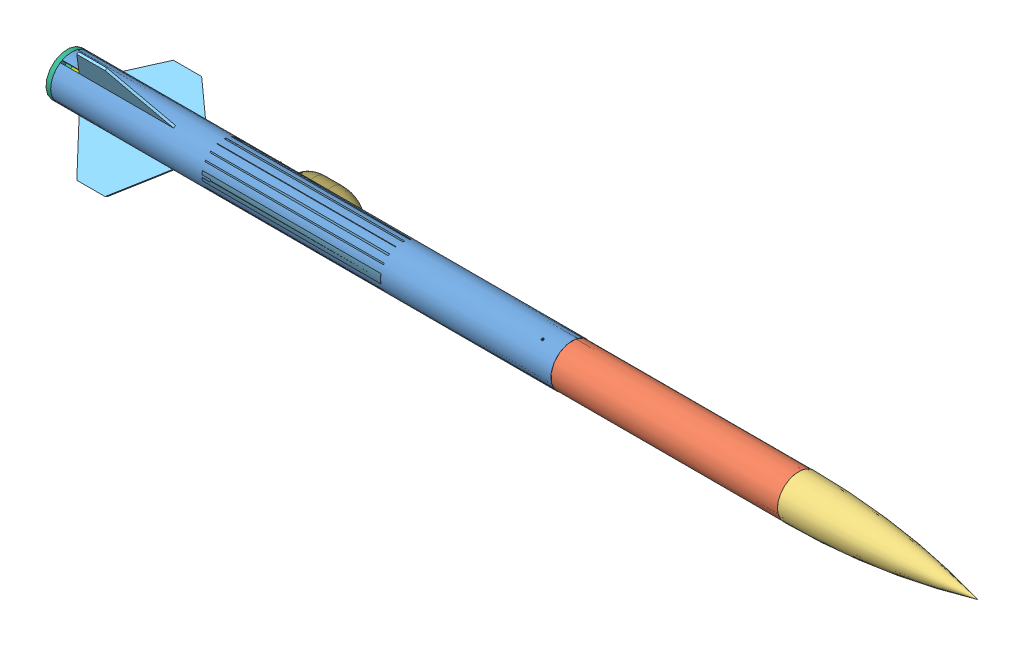
SolidWorks assembly Mudd III Medium Assembly, configuration Default. Lengths in mm.
Overall size (1225.55 149.96 129.87).
100 component instances, 55 part files, 34 mates.
Components (placement in the parent):
- Medium Booster Tube-1: Medium Booster Tube [Default] at (-372.2289 13.0481 9.9626) size (673.1 57.15 57.15)
- Medium Parachute Tube-1: Medium Parachute Tube [Default] at (300.8711 13.0481 9.9626) x (1 0 0) z (0 -0.816689 -0.577078) size (304.8 57.15 57.15)
- Medium Nose Cone-1: Medium Nose Cone [Default] at (542.1711 13.0481 9.9626) x (0 -0.965528 0.260297) z (0 0.260297 0.965528) size (57.15 304.8 57.15)
- Medium Coupler Tube-1: Medium Coupler Tube [Default] at (351.6711 13.0481 9.9626) x (-1 0 0) z (0 -0.866025 -0.5) size (101.6 53.98 53.98)
- Medium Fin-1: Medium Fin [Default] at (-346.8289 -10.8518 25.5943) x (1 0 0) z (0 -0.5 -0.866025) size (127 65.09 3.17)
- Medium Fin-2: Medium Fin [Default] at (-346.8289 38.5356 22.8447) x (1 0 0) z (0 -0.5 0.866025) size (127 65.09 3.17)
- Medium Fin-3: Medium Fin [Default] at (-346.8289 11.4606 -18.5513) x (1 0 0) z (0 1 0) size (127 65.09 3.17)
- Medium Motor Adapter-1: Medium Motor Adapter [Default] at (-372.2289 13.0481 9.9626) x (1 0 0) z (0 0.828794 0.559554) size (234.95 57.15 57.15)
- Medium Center Ring-1: Medium Center Ring [Default] at (-346.8289 13.0481 9.9626) x (0 0.296163 0.955137) z (-1 0 0) size (53.98 53.98 12.7)
- Medium Center Ring-2: Medium Center Ring [Default] at (-169.0289 13.0481 9.9626) x (0 0.277869 0.960619) z (-1 0 0) size (53.98 53.98 12.7)
- total assem-1: total assem [Default] at (-58.9172 86.7196 7.1089) x (0 1 0) z (-1 0 0) size (57.15 75.5 240.21)
  - small ccd assem-1: small ccd assem [Default] at (0.6838 4.0163 -14.4433) size (21.97 25.91 29.31)
    - CCD back card-1: CCD back card [Default] at (-63.2621 8.497 25.622) size (21.97 25.91 6.6)
    - CCD-1: CCD [Default] at (-74.2476 21.8241 33.115) x (0 0 1) z (0 -1 0) size (24.1 21.97 25.91)
  - transmitter-1: transmitter [Default] at (-74.5115 28.118 1.5267) x (1 0 0) z (0 0 -1) size (21.79 25.75 7.11)
  - holder piece full-1: holder piece full [Default] at (-73.6715 -24.6441 89.7205) x (0 0 1) z (-1 0 0) size (78.74 36.53 25.4)
  - shroud-1: shroud [Default] at (-73.6888 25.7213 35.9945) x (0.000325 0 -1) z (1 0 0.000325) size (87.63 29.9 39.12)
  - mirror piece 1by1inch-1: mirror piece 1by1inch [Default] at (-60.9715 15.1368 37.7322) x (1 0 0) z (0 -0.906308 0.422618) size (25.4 25.4 3.2)
  - Mudd III medium tube demo-1: Mudd III medium tube demo [Default] at (-73.666 -2.8537 250.8571) x (0 0 -1) z (0 1 0) size (240.21 57.15 57.15)
  - tab-1: tab [Default] at (-73.666 25.7213 -6.4951) x (0 0 -1) z (1 0 0) size (19.69 10.34 6.35)
- NewAvionicsBay2-1: NewAvionicsBay2 [Default] at (108.4854 -12.4721 24.3916) x (1 0 0) z (0 1 0) size (359.89 53.34 55.74)
  - AvionicsMainBoard-1: AvionicsMainBoard [Default] at (-136.1657 8.079 23.6534) size (349.25 53.34 3.81)
  - 9V battery-1: 9V battery [Default] at (-17.1552 23.2413 23.6534) x (1 0 0) z (0 0 -1) size (46.99 25.4 16.52)
  - IMUBoard-1: IMUBoard [Default] at (-199.5485 3.632 31.1574) x (1 0 0) z (0 0 -1) size (73 23 14.43)
    - IMUMainBoard-1: IMUMainBoard [Default] at (-36.8639 8.2406 13.8541) size (73 23 2)
    - MPXA4115-1: MPXA4115 [Default] at (18.9073 2.9523 15.8541) x (0 -1 0) z (0 0 1) size (18.12 12.32 7.62)
    - AD8608-1: AD8608 [Default] at (15.2114 -11.4075 13.8541) x (1 0 0) z (0 0 -1) size (5 6.4 1.2)
    - AD8608-2: AD8608 [Default] at (14.8718 -1.2991 13.8541) x (1 0 0) z (0 0 -1) size (5 6.4 1.2)
    - ADXL78-1: ADXL78 [Default] at (-6.9369 -1.9207 15.8541) x (0 -1 0) z (0 0 1) size (5 5 1.98)
    - REF19x-1: REF19x [Default] at (-22.4189 6.9447 15.8541) x (0 -1 0) z (0 0 1) size (5 6.2 1.75)
    - IDG300-1: IDG300 [Default] at (-3.0205 -1.1058 15.8541) size (6 6 1.4)
    - 53048-1410-1: 53048-1410 [Default] at (33.2198 -3.0194 17.6041) x (0 -1 0) z (1 0 0) size (19.25 5.8 5.5)
    - 53048-0310-1: 53048-0310 [Default] at (-34.0557 4.9779 17.6041) x (0 1 0) z (-1 0 0) size (5.5 5.8 5.5)
    - 53048-0410-1: 53048-0410 [Default] at (-34.0379 -2.2079 17.6041) x (0 1 0) z (-1 0 0) size (6.75 5.8 5.5)
    - 53048-0510-1: 53048-0510 [Default] at (-34.0353 -10.4916 17.6041) x (0 1 0) z (-1 0 0) size (8 5.8 5.5)
    - AccelDB-1: AccelDB [Default] at (-23.5295 2.2949 14.7757) x (0 1 0) z (1 0 0) size (17 11.63 4.63)
      - 3216Pkg-1: 3216Pkg [Default] at (-3.7758 3.176 4.084) x (0 1 0) z (0 0 1) size (3.2 1.6 1.6)
      - 1206Pkg-1: 1206Pkg [Default] at (-11.4283 4.1288 4.084) x (0 1 0) z (0 0 1) size (3.2 1.6 1.6)
      - 0805Pkg-1: 0805Pkg [Default] at (-10.2284 4.3883 7.259) x (0 1 0) z (0 0 1) size (2 1.25 1.25)
      - 0805Pkg-2: 0805Pkg [Default] at (-12.0972 4.3652 7.259) x (0 1 0) z (0 0 1) size (2 1.25 1.25)
      - ADXL320-1: ADXL320 [Default] at (-5.3524 7.1765 7.259) size (4 4 1.45)
      - AccelDB-1: AccelDB [Default] at (-15.2264 1.0784 5.684) size (17 8 1.57)
      - HeaderPin-2: HeaderPin [Default] at (0.7701 -0.5264 5.684) x (1 0 0) z (0 1 0) size (0.64 0.64 9.53)
      - HeaderPin-3: HeaderPin [Default] at (-14.903 -0.6387 5.684) x (1 0 0) z (0 1 0) size (0.64 0.64 9.53)
      - HeaderPin-4: HeaderPin [Default] at (-14.8947 -0.6469 7.894) x (1 0 0) z (0 1 0) size (0.64 0.64 9.53)
      - HeaderPin-5: HeaderPin [Default] at (0.7664 -0.543 7.894) x (1 0 0) z (0 1 0) size (0.64 0.64 9.53)
    - GyroDB-1: GyroDB [Default] at (-0.6385 5.9144 16.4856) x (1 0 0) z (0 -1 0) size (17 14.43 4.58)
      - GyroDBoard-1: GyroDBoard [Default] at (-12.0524 9.3685 -0.0049) size (17 10.7 1.57)
      - 3216Pkg-1: 3216Pkg [Default] at (-0.8029 4.0431 -1.6049) x (0 1 0) z (0 0 1) size (3.2 1.6 1.6)
      - 1206Pkg-1: 1206Pkg [Default] at (-4.4709 0.5573 -1.6049) x (0 1 0) z (0 0 1) size (3.2 1.6 1.6)
      - 1206Pkg-2: 1206Pkg [Default] at (-4.6902 4.9535 -1.6049) x (0 1 0) z (0 0 1) size (3.2 1.6 1.6)
      - 0805Pkg-1: 0805Pkg [Default] at (-7.0362 1.6074 1.4951) x (0 1 0) z (0 0 1) size (2 1.25 1.25)
      - 0805Pkg-2: 0805Pkg [Default] at (-7.0321 4.6376 1.5701) x (0 1 0) z (0 0 1) size (2 1.25 1.25)
      - IDG300-1: IDG300 [Default] at (-4.083 6.8921 1.5701) size (6 6 1.4)
      - HeaderPin-1: HeaderPin [Default] at (3.9124 3.0877 -0.6399) x (0.999938 -0.011165 0) z (-0.011165 -0.999938 0) size (0.64 0.64 9.53)
      - HeaderPin-2: HeaderPin [Default] at (3.8089 3.0739 1.5701) x (0.999992 0.00401 0) z (0.00401 -0.999992 0) size (0.64 0.64 9.53)
      - HeaderPin-3: HeaderPin [Default] at (-11.5657 2.5564 1.5701) x (1 0 0) z (0 -1 0) size (0.64 0.64 9.53)
      - HeaderPin-4: HeaderPin [Default] at (-11.5519 2.6099 -0.6399) x (1 0 0) z (0 -1 0) size (0.64 0.64 9.53)
    - AD8608-5: AD8608 [Default] at (-8.3767 -4.6541 13.8541) x (-1 0 0) z (0 0 -1) size (5 6.4 1.2)
    - AD8608-6: AD8608 [Default] at (-0.2194 4.1606 13.8541) x (-1 0 0) z (0 0 -1) size (5 6.4 1.2)
    - REF19x-3: REF19x [Default] at (-27.9582 6.764 13.8541) x (0 -1 0) z (0 0 -1) size (5 6.2 1.75)
  - SigCond-1: SigCond [Default] at (55.7433 7.466 27.9177) x (-1 0 0) z (0 0 -1) size (40 23 6.27)
    - SigCond-1: SigCond [Default] at (-14.6509 -4.244 10.6143) size (40 23 1.57)
    - AD8608-1: AD8608 [Default] at (3.1067 8.1664 10.6143) x (0 -1 0) z (0 0 -1) size (5 6.4 1.2)
    - AD8608-2: AD8608 [Default] at (8.6587 7.5077 12.1891) x (0 -1 0) z (0 0 1) size (5 6.4 1.2)
    - REF19x-1: REF19x [Default] at (2.8146 17.9328 12.1891) x (0 -1 0) z (0 0 1) size (5 6.2 1.75)
    - 53048-1010-1: 53048-1010 [Default] at (-11.8656 3.4034 13.9391) x (0 1 0) z (-1 0 0) size (14.25 5.8 5.5)
    - 53048-1210-1: 53048-1210 [Default] at (22.5911 4.1581 13.9391) x (0 -1 0) z (1 0 0) size (16.75 5.8 5.5)
  - SwitchPlate-1: SwitchPlate [Default] at (85.8509 10.5974 25.1267) x (0 1 0) z (0 0 1) size (31.75 24.13 13.32)
    - SwitchPlate-1: SwitchPlate [Default] at (-12.5007 -3.0767 8.6867) size (31.75 24.13 1.57)
    - ScrewSwitch-1: ScrewSwitch [Default] at (3.373 8.9378 10.2615) x (0 1 0) z (0 0 1) size (7.92 7.37 13.32)
  - 5VBoard-1: 5VBoard [Default] at (-89.5319 8.7054 29.3839) x (-1 0 0) z (0 0 -1) size (92.07 27.94 17.78)
    - 5VPower-1: 5VPower [Default] at (-41.4694 20.784 7.7625) size (92.08 27.94 1.57)
    - 9VClip-1: 9VClip [Default] at (14.6682 14.1315 9.3373) x (0 -1 0) z (-1 0 0) size (9.65 17.02 7.26)
    - 9VClip-2: 9VClip [Default] at (14.1531 0.4986 9.3373) x (0 -1 0) z (-1 0 0) size (9.65 17.02 7.26)
    - ScrewSwitch-1: ScrewSwitch [Default] at (28.3109 6.7817 9.3373) size (7.92 7.37 13.32)
  - RDASTransmitter-1: RDASTransmitter [Default] at (-146.7869 -1.9294 33.8134) size (95.9 28 17.4)
  - AntennaRDAS-1: AntennaRDAS [Default] at (-151.5106 12.0706 43.9644) x (0 0.94972 0.3131) z (0 -0.3131 0.94972) size (17.21 92.63 16.7)
  - 9V battery-2: 9V battery [Default] at (-85.0106 24.0842 20.0466) x (1 0 0) z (0 0 -1) size (46.99 25.4 16.52)
  - rdas started-1: rdas started [Default] at (22.7124 41.4238 33.8134) x (1 0 0) z (0 0 -1) size (94.13 28 20.9)
  - AvionicsForwardDisk-1: AvionicsForwardDisk [Default] at (93.3256 14.429 25.5203) x (0 0 -1) z (1 0 0) size (53.34 53.34 6.35)
  - AvionicsAftDisk-3: AvionicsAftDisk [Default] at (-243.2244 14.429 25.5584) x (0 0 1) z (-1 0 0) size (53.34 53.34 6.35)
  - patchbay-1: patchbay [Default] at (94.5977 -15.4317 39.9493) x (0 -1 0) z (1 0 0) size (35.05 35.05 16.14)
    - patchbay disk-1: patchbay disk [Default] at (-29.8607 14.429 5.0779) size (35.05 35.05 1.75)
    - 53048-0510-1: 53048-0510 [Default] at (-39.1051 14.4036 9.5805) x (0 -1 0) z (0 0 1) size (8 5.8 5.5)
    - 53048-1410-1: 53048-1410 [Default] at (-30.0832 5.1164 2.3279) x (-1 0 0) z (0 0 -1) size (19.25 5.8 5.5)
    - 53048-1010-1: 53048-1010 [Default] at (-31.8902 22.3247 2.3279) x (-1 0 0) z (0 0 -1) size (14.25 5.8 5.5)
    - patchbay pins-1: patchbay pins [Default] at (-14.7709 42.7152 6.8305) x (0 1 0) z (0 0 1) size (20 14 8.89)
- Ejection Assembly-1: Ejection Assembly [Default] at (258.3491 5.0129 22.6223) x (0 -0.14468 0.989478) z (-1 0 0) size (50.8 49.29 12.7)
  - Drogue Bulk Head (without aluminum)-1: Drogue Bulk Head (without aluminum) [Default] at (-13.689 6.119 0.658) size (50.8 49.29 3.81)
  - Drouge Bulk Head (with aluminum)-1: Drouge Bulk Head (with aluminum) [Default] at (-13.689 6.119 8.278) size (50.8 43.36 3.81)
  - Drogue Bulk Head Screw Insert-1: Drogue Bulk Head Screw Insert [Default] at (-13.689 12.215 13.358) x (1 0 0) z (0 1 0) size (19.05 12.7 19.05)
  - Booster Bulkhead Aluminum (with thread)-1: Booster Bulkhead Aluminum (with thread) [Default] at (-31.2912 -12.677 4.468) size (35.56 15.24 4.06)
  - Booster Bulkhead Aluminum (without thread)-1: Booster Bulkhead Aluminum (without thread) [Default] at (-31.2912 -12.677 8.532) size (35.56 15.24 4.06)
- Retention Assembly-1: Retention Assembly [Default] at (551.1746 -1.4552 15.5793) x (0 -0.709837 0.704366) z (-1 0 0) size (51.82 51.82 16)
  - Bulkhead3-1: Bulkhead3 [Default] at (-14.2512 6.2286 1.3835) size (50.8 50.8 3.81)
  - Booster Bulkhead-1: Booster Bulkhead [Default] at (-14.2512 6.2286 5.1935) size (51.82 51.82 3.81)
  - Booster Bulkhead Aluminum (without thread)-1: Booster Bulkhead Aluminum (without thread) [Default] at (3.5288 -1.3914 17.1315) x (-1 0 0) z (0 0 -1) size (35.56 15.24 4.06)
  - Booster Bulkhead Aluminum (with thread)-1: Booster Bulkhead Aluminum (with thread) [Default] at (-32.0312 -1.3914 1.1295) size (35.56 15.24 4.06)
  - Booster Bulkhead Aluminum (without thread)-2: Booster Bulkhead Aluminum (without thread) [Default] at (-32.0312 -1.3914 9.0035) size (35.56 15.24 4.06)
Mates (geometry in assembly coordinates):
- Concentric1: concentric aligned: cylinder of Medium Booster Tube-1; cylinder of Medium Parachute Tube-1
- Concentric2: concentric anti-aligned: cylinder of Medium Parachute Tube-1; cylinder of Medium Nose Cone-1
- Coincident2: coincident anti-aligned: plane of Medium Parachute Tube-1 through (605.6711 13.0481 9.9626) normal (1 0 0); plane of Medium Nose Cone-1 through (605.6711 39.1053 2.9378) normal (-1 0 0)
- Concentric3: concentric anti-aligned: cylinder of Medium Parachute Tube-1; cylinder of Medium Coupler Tube-1
- Distance1: distance = 50.8 mm aligned: plane of Medium Parachute Tube-1 through (300.8711 13.0481 9.9626) normal (-1 0 0); plane of Medium Coupler Tube-1 through (250.0711 13.0481 9.9626) normal (-1 0 0)
- Concentric4: concentric aligned: cylinder of Medium Booster Tube-1; cylinder of Medium Coupler Tube-1
- Concentric5: concentric aligned: cylinder of Medium Booster Tube-1; cylinder of Medium Motor Adapter-1
- Concentric8: concentric anti-aligned: cylinder of Medium Motor Adapter-1; cylinder of Medium Center Ring-1
- Concentric9: concentric anti-aligned: cylinder of Medium Motor Adapter-1; cylinder of Medium Center Ring-2
- Distance6: distance = 12.7 mm anti-aligned: plane of Medium Motor Adapter-1 through (-372.2289 13.0481 9.9626) normal (1 0 0); plane of Medium Center Ring-1 through (-359.5289 13.0481 9.9626) normal (-1 0 0)
- Distance8: distance = 25.4 mm aligned: plane of Medium Motor Adapter-1 through (-143.6289 13.0481 9.9626) normal (1 0 0); plane of Medium Center Ring-2 through (-169.0289 13.0481 9.9626) normal (1 0 0)
- Coincident36: coincident: line of Medium Fin-3; cylinder of Medium Motor Adapter-1
- Coincident37: coincident: line of Medium Fin-2; cylinder of Medium Motor Adapter-1
- Coincident38: coincident: line of Medium Fin-1; cylinder of Medium Motor Adapter-1
- Coincident39: coincident: line of Medium Fin-3; cylinder of Medium Motor Adapter-1
- Coincident40: coincident: line of Medium Fin-1; cylinder of Medium Motor Adapter-1
- Coincident42: coincident: line of Medium Fin-2; cylinder of Medium Motor Adapter-1
- Coincident43: coincident anti-aligned: plane of Medium Fin-2 through (-346.8289 36.9481 25.5943) normal (-1 0 0); plane of Medium Center Ring-1 through (-346.8289 13.0481 9.9626) normal (1 0 0)
- Coincident44: coincident anti-aligned: plane of Medium Fin-1 through (-346.8289 -12.4393 22.8447) normal (-1 0 0); plane of Medium Center Ring-1 through (-346.8289 13.0481 9.9626) normal (1 0 0)
- Coincident45: coincident anti-aligned: plane of Medium Fin-3 through (-346.8289 14.6356 -18.5513) normal (-1 0 0); plane of Medium Center Ring-1 through (-346.8289 13.0481 9.9626) normal (1 0 0)
- Parallel2: parallel anti-aligned: plane of Medium Booster Tube-1 through (-219.8289 11.4606 -18.6124) normal (0 1 0); plane of Medium Fin-3 through (-346.8289 11.4606 -75.7013) normal (0 -1 0)
- Parallel3: parallel anti-aligned: plane of Medium Booster Tube-1 through (-219.8289 47.6465 28.1049) normal (0 -0.5 0.866025); plane of Medium Fin-2 through (-346.8289 88.029 51.4197) normal (0 0.5 -0.866025)
- Coincident49: coincident anti-aligned: plane of Medium Booster Tube-1 through (-372.2289 13.0481 9.9626) normal (-1 0 0); plane of Medium Motor Adapter-1 through (-372.2289 13.0481 9.9626) normal (1 0 0)
- Concentric10: concentric anti-aligned: circle of Medium Coupler Tube-1 centre (250.0711 13.0481 9.9626) axis (-1 0 0); circle of NewAvionicsBay2-1/AvionicsForwardDisk-1 centre (208.1611 13.0481 9.9626) axis (1 0 0)
- Parallel5: parallel aligned: line of total assem-1/holder piece full-1; line of NewAvionicsBay2-1/AvionicsMainBoard-1
- Parallel6: parallel aligned: line of total assem-1/holder piece full-1; line of NewAvionicsBay2-1/AvionicsMainBoard-1
- Coincident58: coincident anti-aligned: plane of total assem-1/holder piece full-1 through (-52.8239 16.2231 5.2201) normal (1 0 0); plane of NewAvionicsBay2-1/AvionicsMainBoard-1 through (-52.8239 14.9912 5.2201) normal (-1 0 0)
- Parallel8: parallel aligned: plane of Medium Fin-3 through (-346.8289 14.6356 -75.7013) normal (0 1 0); plane of NewAvionicsBay2-1/AvionicsMainBoard-1 through (201.8111 14.9912 -16.7074) normal (0 1 0)
- Distance9: distance = 2.54 mm anti-aligned: plane of Medium Motor Adapter-1 through (-143.6289 13.0481 9.9626) normal (1 0 0); plane of NewAvionicsBay2-1/AvionicsAftDisk-3 through (-141.0889 13.0862 9.9626) normal (-1 0 0)
- Concentric11: concentric anti-aligned: circle of NewAvionicsBay2-1/AvionicsForwardDisk-1 centre (208.1611 13.0481 9.9626) axis (1 0 0); circle of Medium Coupler Tube-1 centre (250.0711 13.0481 9.9626) axis (-1 0 0)
- Concentric12: concentric aligned: circle of Medium Coupler Tube-1 centre (250.0711 13.0481 9.9626) axis (-1 0 0); circle of Ejection Assembly-1/Drogue Bulk Head (without aluminum)-1 centre (257.6911 13.0481 9.9626) axis (-1 0 0)
- Coincident59: coincident aligned: plane of Medium Coupler Tube-1 through (250.0711 13.0481 9.9626) normal (-1 0 0); plane of Ejection Assembly-1/Drouge Bulk Head (with aluminum)-1 through (250.0711 13.0481 9.9626) normal (-1 0 0)
- Concentric14: concentric anti-aligned: circle of Medium Nose Cone-1 centre (542.1711 13.0481 9.9626) axis (1 0 0); circle of Retention Assembly-1/Bulkhead3-1 centre (549.7911 13.0481 9.9626) axis (-1 0 0)
- Coincident63: coincident aligned: unknown of Medium Nose Cone-1; unknown of Retention Assembly-1/Booster Bulkhead-1
